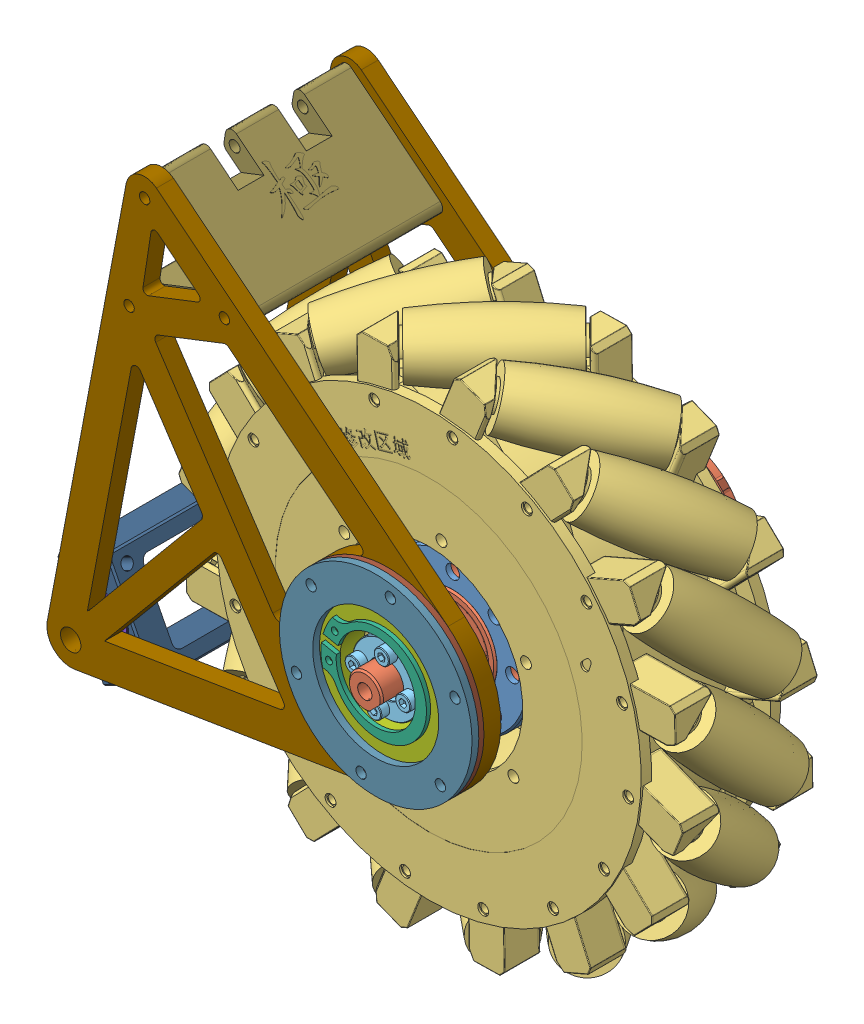
SolidWorks assembly 轮组1, configuration 默认. Lengths in mm.
Overall size (208.38 201.88 98.4).
19 component instances, 15 part files, 43 mates.
Components (placement in the parent):
- 轮组3508机加工件-1: 轮组3508机加工件 [默认] at origin size (56.5 56.5 41)
- RM3508直流无刷减速电机-1: RM3508直流无刷减速电机 [默认] at (-8.7166 16.154 -46.941) x (-0.922142 -0.386852 0) z (0 0 1) size (42 44.97 98.4)
- HEXROLL_16-D154-2.0-1: HEXROLL_16-D154-2.0 [默认] at (0 0 48.05) x (0.919361 0.393415 0) z (0 0 1) size (153.78 153.78 41)
- 轮组转动机加件-1: 轮组转动机加件 [默认] at (0 0 42.1) x (0 0 1) z (0.393415 -0.919361 0) size (22 67 67) (hidden)
- 轮组机加件-1: 轮组机加件 [默认] at (0 0 18) x (0 0 -1) z (0.8838 -0.467866 0) size (8 66 66)
- 胀紧套 ZZ21—10x20x13-1: 胀紧套 ZZ21—10x20x13 [默认] at (0 0 47.6) x (0.988286 -0.152615 0) z (0 0 1) size (20 20 15.5)
- GB894．2-86轴用弹性挡圈B型25-1: GB894．2-86轴用弹性挡圈B型25 [默认] at (0 0 62.2) x (-0.199141 -0.979971 0) z (0 0 1) size (28.2 30.93 1.2)
- 法兰轴承-1: 法兰轴承 [25*37*7-1.5] at (0 0 61.6) x (-0.301635 0.953423 0) z (-0.953423 -0.301635 0) size (40 7 40)
- 深沟球轴承-1: 深沟球轴承 [45x58x7] at (0 0 10) x (0.721643 -0.692266 0) z (-0.692266 -0.721643 0) size (58 7 58)
- 轮组转板-1: 轮组转板 [内侧板] at (-71.3089 86.3658 -2.5) x (-0.984808 0.173648 0) z (0 0 -1) size (127.26 144.78 5)
- 轮组转板-2: 轮组转板 [外侧板] at (-71.3089 86.3658 57.6) x (-0.984808 0.173648 0) z (0 0 -1) size (126.26 144.78 5)
- 轮组转点机加工件-1: 轮组转点机加工件 [默认] at (-93.0128 -36.7235 27.55) x (0 0 1) z (-0.888839 -0.45822 0) size (45 30 17)
- 轮组垫块-1: 轮组垫块 [默认] at (0 0 60.1) x (0.984808 -0.173648 0) z (0 0 1) size (56.5 56.5 1.5)
- 悬挂安装打印件-1: 悬挂安装打印件 [默认] at (-71.3089 86.3658 27.5) x (0.931996 0.362469 0) z (0 0 1) size (37.46 32.98 55)
- 深沟球轴承-2: 深沟球轴承 [6x13x5] at (-93.0128 -36.7235 5.05) x (-0.458973 -0.88845 0) z (-0.88845 0.458973 0) size (13 5 13)
- 深沟球轴承-3: 深沟球轴承 [6x13x5] at (-93.0128 -36.7235 45.05) x (0.999149 0.04124 0) z (0.04124 -0.999149 0) size (13 5 13)
- 推力球轴承-1: 推力球轴承 [F5-10M 5*10*4] at (-93.0128 -36.7235 0.05) x (0.246634 -0.969109 0) z (-0.969109 -0.246634 0) size (10 4 10)
- 推力球轴承-2: 推力球轴承 [F5-10M 5*10*4] at (-93.0128 -36.7235 50.05) x (0.140865 -0.990029 0) z (-0.990029 -0.140865 0) size (10 4 10)
- 轮组轴承压板-1: 轮组轴承压板 [默认] at (0 0 61.6) x (0.984808 -0.173648 0) z (0 0 1) size (56.5 56.5 2)
Mates (geometry in assembly coordinates):
- 同心1: concentric aligned: cylinder of 轮组3508机加工件-1 through (0 0 41) axis (0 0 -1) radius 21.05; cylinder of RM3508直流无刷减速电机-1 through (0 0 29.5) axis (0 0 -1) radius 21
- 重合1: coincident anti-aligned: plane of 轮组3508机加工件-1 through (0 0 39.5) normal (0 0 -1); plane of RM3508直流无刷减速电机-1 through (0 13 39.5) normal (0 0 1)
- 同心2: concentric anti-aligned: cylinder of 轮组3508机加工件-1 through (0 0 17) axis (0 0 -1) radius 22.5; cylinder of HEXROLL_16-D154-2.0-1 through (0 0 38) axis (0 0 1) radius 27.55
- 同心3: concentric anti-aligned: cylinder of RM3508直流无刷减速电机-1 through (0 0 66.8) axis (0 0 1) radius 5; cylinder of 轮组转动机加件-1 through (0 0 42.1) axis (0 0 -1) radius 13.5
- 重合2: coincident anti-aligned: plane of HEXROLL_16-D154-2.0-1 through (0 0 45.1) normal (0 0 -1); plane of 轮组转动机加件-1 through (-26.8132 -6.1076 45.1) normal (0 0 1)
- 同心4: concentric aligned: cylinder of HEXROLL_16-D154-2.0-1 through (-30.2258 -6.885 40.5745) axis (0 0 1) radius 1.6; cylinder of 轮组转动机加件-1 through (-30.2258 -6.885 45.1) axis (0 0 1) radius 1.25
- 同心5: concentric anti-aligned: cylinder of 轮组3508机加工件-1 through (0 0 41) axis (0 0 -1) radius 22.25; cylinder of 轮组机加件-1 through (0 0 18) axis (0 0 1) radius 33
- 重合3: coincident anti-aligned: plane of 轮组3508机加工件-1 through (0 0 10) normal (0 0 1); plane of 轮组机加件-1 through (20.4214 25.9223 10) normal (0 0 -1)
- 重合4: coincident anti-aligned: plane of HEXROLL_16-D154-2.0-1 through (0 0 10) normal (0 0 1); plane of 轮组机加件-1 through (20.4214 25.9223 10) normal (0 0 -1)
- 同心6: concentric anti-aligned: cylinder of RM3508直流无刷减速电机-1 through (0 0 66.8) axis (0 0 1) radius 5; cylinder of 胀紧套 ZZ21—10x20x13-1 through (0 0 60.6) axis (0 0 -1) radius 10
- 重合5: coincident anti-aligned: plane of 轮组转动机加件-1 through (-13.1628 -2.9983 62.8) normal (0 0 -1); plane of GB894．2-86轴用弹性挡圈B型25-1 through (-0.7705 0.3085 62.8) normal (0 0 1)
- 同心8: concentric aligned: cylinder of 轮组转动机加件-1 through (0 0 42.1) axis (0 0 -1) radius 11.6; cylinder of GB894．2-86轴用弹性挡圈B型25-1 through (0 0 62.8) axis (0 0 -1) radius 14.1
- 同心9: concentric aligned: cylinder of 轮组转动机加件-1 through (0 0 54.6) axis (0 0 1) radius 12.5; cylinder of 法兰轴承-1 through (0 0 54.6) axis (0 0 1) radius 18.5
- 重合6: coincident anti-aligned: plane of GB894．2-86轴用弹性挡圈B型25-1 through (-0.7705 0.3085 61.6) normal (0 0 -1); plane of 法兰轴承-1 through (0 0 61.6) normal (0 0 1)
- 重合7: coincident anti-aligned: plane of 轮组机加件-1 through (17.9461 22.7802 17) normal (0 0 -1); plane of 深沟球轴承-1 through (0 0 17) normal (0 0 1)
- 同心10: concentric anti-aligned: cylinder of 轮组机加件-1 through (0 0 18) axis (0 0 1) radius 33; cylinder of 深沟球轴承-1 through (0 0 17) axis (0 0 -1) radius 29
- 重合8: coincident anti-aligned: plane of 轮组3508机加工件-1 through (0 0 0) normal (0 0 -1); plane of 轮组转板-1 through (0 0 0) normal (0 0 1)
- 同心11: concentric anti-aligned: cylinder of 轮组3508机加工件-1 through (0 0 4) axis (0 0 -1) radius 28.25; cylinder of 轮组转板-1 through (0 0 -5) axis (0 0 1) radius 21.05
- 同心13: concentric anti-aligned: cylinder of 轮组3508机加工件-1 through (0 25.5 4) axis (0 0 1) radius 1.65; cylinder of 轮组转板-1 through (0 25.5 5) axis (0 0 -1) radius 2.025
- 同心15: concentric aligned: cylinder of 法兰轴承-1 through (0 0 54.6) axis (0 0 1) radius 18.5; cylinder of 轮组转板-2 through (0 0 55.1) axis (0 0 1) radius 18.5
- 重合9: coincident anti-aligned: plane of 法兰轴承-1 through (0 0 60.1) normal (0 0 -1); plane of 轮组转板-2 through (0 0 60.1) normal (0 0 1)
- 同心16: concentric aligned: cylinder of 轮组转板-1 through (-77.9977 81.764 -5) axis (0 0 1) radius 1.525; cylinder of 轮组转板-2 through (-77.9977 81.764 55.1) axis (0 0 1) radius 1.525
- 同心17: concentric aligned: cylinder of 轮组转板-1 through (-100.9634 -48.4809 -5) axis (0 0 1) radius 3; cylinder of 轮组转点机加工件-1 through (-100.9634 -48.4809 -7.95) axis (0 0 1) radius 4
- 宽度1: width anti-aligned: plane of 轮组转板-1 through (0 0 0) normal (0 0 1); plane of 轮组转板-2 through (0 0 55.1) normal (0 0 -1); plane of 轮组转点机加工件-1 through (-104.7248 -65.3065 5.05) normal (0 0 -1); plane of 轮组转点机加工件-1 through (-104.7248 -65.3065 50.05) normal (0 0 1)
- 重合10: coincident anti-aligned: plane of 轮组转板-2 through (0 0 60.1) normal (0 0 1); plane of 轮组垫块-1 through (0 0 60.1) normal (0 0 -1)
- 同心18: concentric anti-aligned: cylinder of 法兰轴承-1 through (0 0 60.1) axis (0 0 1) radius 20; cylinder of 轮组垫块-1 through (0 0 61.6) axis (0 0 -1) radius 28.25
- 同心19: concentric anti-aligned: cylinder of 轮组转板-1 through (-77.9977 81.764 -5) axis (0 0 1) radius 1.525; cylinder of 悬挂安装打印件-1 through (-77.9977 81.764 55) axis (0 0 -1) radius 1.6
- 同心20: concentric aligned: cylinder of 轮组转板-1 through (-80.2109 51.8458 26.54) axis (0 0 -1) radius 1.525; cylinder of 悬挂安装打印件-1 through (-80.2109 51.8458 55) axis (0 0 -1) radius 1.6
- 同心21: concentric aligned: cylinder of 轮组转点机加工件-1 through (-100.9634 -48.4809 10.05) axis (0 0 -1) radius 6.5; cylinder of 深沟球轴承-2 through (-100.9634 -48.4809 10.05) axis (0 0 -1) radius 6.5
- 重合14: coincident anti-aligned: plane of 轮组转点机加工件-1 through (-100.9634 -48.4809 10.05) normal (0 0 -1); plane of 深沟球轴承-2 through (-100.9634 -48.4809 10.05) normal (0 0 1)
- 同心22: concentric anti-aligned: cylinder of 轮组转点机加工件-1 through (-100.9634 -48.4809 45.05) axis (0 0 1) radius 6.5; cylinder of 深沟球轴承-3 through (-100.9634 -48.4809 50.05) axis (0 0 -1) radius 6.5
- 重合15: coincident anti-aligned: plane of 轮组转点机加工件-1 through (-100.9634 -48.4809 45.05) normal (0 0 1); plane of 深沟球轴承-3 through (-100.9634 -48.4809 45.05) normal (0 0 -1)
- 同心23: concentric anti-aligned: cylinder of 轮组转板-1 through (-100.9634 -48.4809 -5) axis (0 0 1) radius 3; cylinder of 推力球轴承-1 through (-100.9634 -48.4809 5.05) axis (0 0 -1) radius 3
- 重合16: coincident anti-aligned: plane of 轮组转点机加工件-1 through (-104.7248 -65.3065 5.05) normal (0 0 -1); plane of 推力球轴承-1 through (-100.9634 -48.4809 5.05) normal (0 0 1)
- 同心24: concentric anti-aligned: cylinder of 轮组转点机加工件-1 through (-100.9634 -48.4809 -7.95) axis (0 0 1) radius 4; cylinder of 推力球轴承-2 through (-100.9634 -48.4809 55.05) axis (0 0 -1) radius 7
- 重合17: coincident anti-aligned: plane of 轮组转点机加工件-1 through (-104.7248 -65.3065 50.05) normal (0 0 1); plane of 推力球轴承-2 through (-100.9634 -48.4809 50.05) normal (0 0 -1)
- 同心25: concentric anti-aligned: cylinder of 轮组转板-2 through (4.2978 24.374 65.1) axis (0 0 -1) radius 1.525; cylinder of 轮组垫块-1 through (4.2978 24.374 55.5745) axis (0 0 1) radius 1.6
- 同心26: concentric aligned: cylinder of 轮组垫块-1 through (0 0 61.6) axis (0 0 -1) radius 28.25; cylinder of 轮组轴承压板-1 through (0 0 63.6) axis (0 0 -1) radius 28.25
- 重合18: coincident anti-aligned: plane of 轮组垫块-1 through (0 0 61.6) normal (0 0 1); plane of 轮组轴承压板-1 through (0 0 61.6) normal (0 0 -1)
- 同心27: concentric anti-aligned: cylinder of 轮组转板-2 through (-23.2574 -8.465 65.1) axis (0 0 -1) radius 1.525; cylinder of 轮组轴承压板-1 through (-23.2574 -8.465 61.6) axis (0 0 1) radius 1.525
- 重合19: coincident anti-aligned: plane of 轮组转板-1 through (0 0 0) normal (0 0 1); plane of 悬挂安装打印件-1 through (-77.9977 81.764 0) normal (0 0 -1)
- 距离1: distance = 3.5 mm aligned: plane of 胀紧套 ZZ21—10x20x13-1 through (0 0 60.6) normal (0 0 1); plane of 轮组转动机加件-1 through (-9.7502 -2.221 64.1) normal (0 0 1)
- 同心28: concentric anti-aligned: cylinder of 轮组3508机加工件-1 through (12.3744 12.3744 46.5) axis (0 0 -1) radius 2; cylinder of RM3508直流无刷减速电机-1 through (12.3744 12.3744 39.5) axis (0 0 1) radius 1.65
